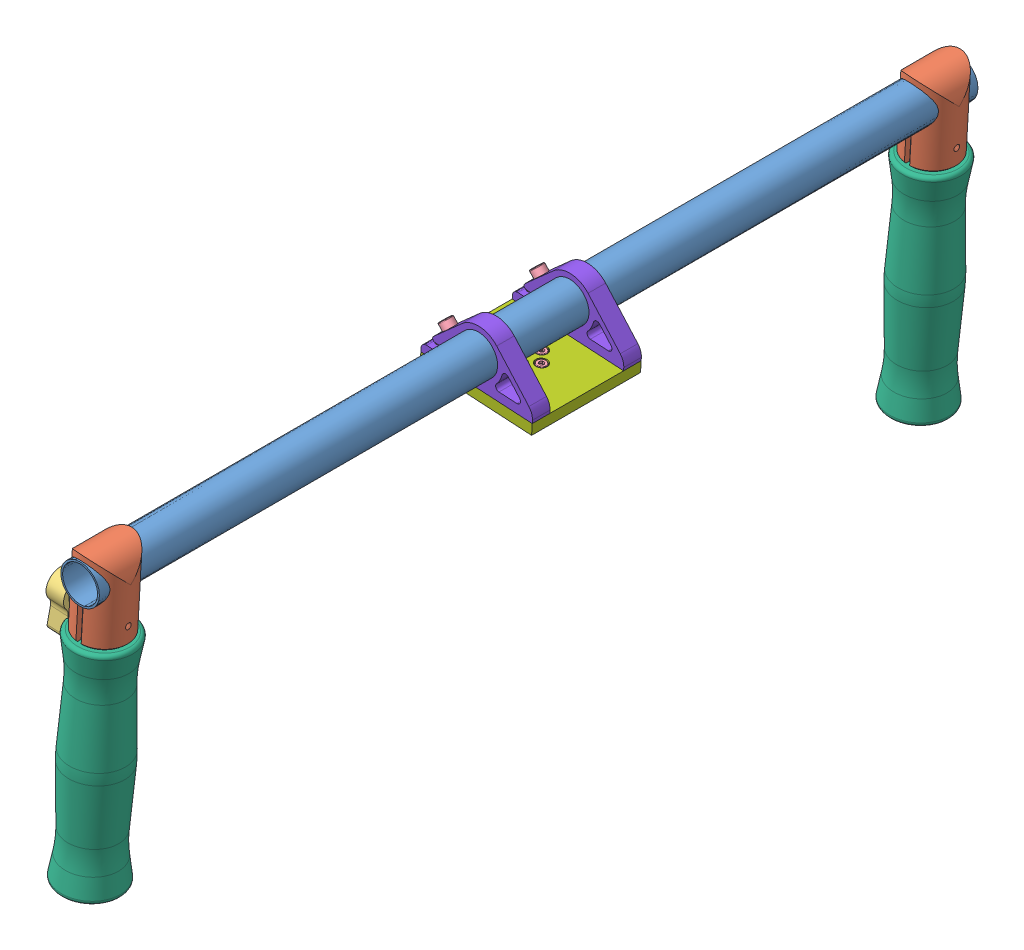
SolidWorks assembly yaw_lowcost_pipe_22mm_holder_4K, configuration По умолчанию. Lengths in mm.
Overall size (66.09 174.99 512.92).
29 component instances, 8 part files, 17 mates.
Components (placement in the parent):
- pipe_22_2_500-1: pipe_22_2_500 [По умолчанию] at (-77.2136 117.9724 -226.0257) x (0.999947 -0.010256 0) z (0 0 1) size (22 22 500)
- handle_holder_22mm-1: handle_holder_22mm [По умолчанию] at (-76.3925 131.9483 259.1774) x (0.998279 -0.058647 0) z (-0.058647 -0.998279 0) size (28 28 45)
- handle_holder_22mm-2: handle_holder_22mm [По умолчанию] at (-76.3925 131.9483 -212.3244) x (0.998279 -0.058647 0) z (-0.058647 -0.998279 0) size (28 28 45)
- flag_screw-4: flag_screw [По умолчанию] at (-77.412 147.1518 -231.8909) x (0.05844 0.994748 0.084026) z (-0.004928 -0.083881 0.996464) size (16 29 29)
  - flag-1: flag [По умолчанию] at (-48.2962 13.0906 23.7085) size (16 10 29)
  - socket head cap screw_din_1-1: socket head cap screw_din_1 [DIN 912 M4 x 25 --- 25N] at (-48.2962 23.0906 23.7085) x (0 -1 0) z (-0.387543 0 0.921852) size (29 7 7)
  - plain washer 6902 type abc_din-1: plain washer 6902 type abc_din [DIN 6902-A4.55] at (-48.2962 13.0906 23.7085) x (0 -1 0) z (-0.000413 0 1) size (1 10 10)
- flag_screw-5: flag_screw [По умолчанию] at (-78.5556 127.6853 303.4175) x (0.008709 0.14824 0.988913) z (-0.057997 -0.987211 0.148496) size (16 29 29)
  - flag-1: flag [По умолчанию] at (-48.2962 13.0906 23.7085) size (16 10 29)
  - socket head cap screw_din_1-1: socket head cap screw_din_1 [DIN 912 M4 x 25 --- 25N] at (-48.2962 23.0906 23.7085) x (0 -1 0) z (-0.387543 0 0.921852) size (29 7 7)
  - plain washer 6902 type abc_din-1: plain washer 6902 type abc_din [DIN 6902-A4.55] at (-48.2962 13.0906 23.7085) x (0 -1 0) z (-0.000413 0 1) size (1 10 10)
- pipe_22_2_500-2: pipe_22_2_500 [150mm] at (-77.976 104.9948 -212.3244) x (-0.658186 0.038667 0.751862) z (-0.058647 -0.998279 0) size (22 22 145)
- pipe_22_2_500-3: pipe_22_2_500 [150mm] at (-77.976 104.9948 259.1774) x (0.99525 -0.058469 0.077844) z (-0.058647 -0.998279 0) size (22 22 145)
- neopren-1: neopren [По умолчанию] at (-79.0316 87.0258 259.1774) x (0.6577 -0.038639 0.752289) z (-0.750994 0.04412 0.658834) size (34.36 127 34.36)
- neopren-2: neopren [По умолчанию] at (-79.0316 87.0258 -212.3244) x (0.998279 -0.058647 0) z (0 0 1) size (34.36 127 34.36)
- lowcost_handle_holder-1: lowcost_handle_holder [По умолчанию] at (-103.6025 70.0667 71.265) x (0 0 1) z (0.058647 0.998279 0) size (62 63.5 46)
  - yaw_lowcost_pipe_22mm_holder_plate-1: yaw_lowcost_pipe_22mm_holder_plate [По умолчанию] at (-54.9011 23.534 26.371) size (62 63.5 6)
  - pipe_22_holder_3-1: pipe_22_holder_3 [По умолчанию] at (-75.9011 23.534 49.371) x (0 -1 0) z (-1 0 0) size (63.5 31 10)
  - pipe_22_holder_3-2: pipe_22_holder_3 [По умолчанию] at (-23.9011 23.534 49.371) x (0 -1 0) z (-1 0 0) size (63.5 31 10)
  - socket head cap screw_din_1-1: socket head cap screw_din_1 [DIN 912 M4 x 6 --- 6N] at (-28.9011 -3.216 26.371) x (0 0 1) z (-1 0 0) size (10 7 7)
  - socket head cap screw_din_1-2: socket head cap screw_din_1 [DIN 912 M4 x 6 --- 6N] at (-28.9011 50.284 26.371) x (0 0 1) z (-1 0 0) size (10 7 7)
  - socket head cap screw_din_1-3: socket head cap screw_din_1 [DIN 912 M4 x 6 --- 6N] at (-80.9011 50.284 26.371) x (0 0 1) z (-1 0 0) size (10 7 7)
  - socket head cap screw_din_1-4: socket head cap screw_din_1 [DIN 912 M4 x 6 --- 6N] at (-80.9011 -3.216 26.371) x (0 0 1) z (-1 0 0) size (10 7 7)
  - socket head cap screw_din_1-5: socket head cap screw_din_1 [DIN 912 M3 x 12 --- 12N] at (-54.9011 29.534 32.371) x (0 0 -1) z (1 0 0) size (15 5.5 5.5)
  - socket head cap screw_din_1-6: socket head cap screw_din_1 [DIN 912 M3 x 12 --- 12N] at (-48.9011 23.534 32.371) x (0 0 -1) z (1 0 0) size (15 5.5 5.5)
  - socket head cap screw_din_1-7: socket head cap screw_din_1 [DIN 912 M3 x 12 --- 12N] at (-60.9011 23.534 32.371) x (0 0 -1) z (1 0 0) size (15 5.5 5.5)
  - socket head cap screw_din_1-8: socket head cap screw_din_1 [DIN 912 M3 x 12 --- 12N] at (-54.9011 17.534 32.371) x (0 0 -1) z (1 0 0) size (15 5.5 5.5)
  - socket head cap screw_din_1-11: socket head cap screw_din_1 [DIN 912 M4 x 16 --- 16N] at (-80.9011 -0.2649 51.0031) x (0 0.707898 -0.706314) z (0.706314 0.499999 0.50112) size (20 7 7)
  - socket head cap screw_din_1-12: socket head cap screw_din_1 [DIN 912 M4 x 16 --- 16N] at (-28.9011 -0.2649 51.0031) x (0 0.707898 -0.706314) z (0.706314 0.499999 0.50112) size (20 7 7)
Mates (geometry in assembly coordinates):
- Концентричный27: concentric anti-aligned: cylinder of pipe_22_2_500-1 through (-77.2136 117.9724 273.9743) axis (0 0 -1) radius 11; cylinder of handle_holder_22mm-1 through (-77.2136 117.9724 245.1774) axis (0 0 1) radius 10.925
- Концентричный28: concentric anti-aligned: cylinder of pipe_22_2_500-1 through (-77.2136 117.9724 273.9743) axis (0 0 -1) radius 11; cylinder of handle_holder_22mm-2 through (-77.2136 117.9724 -226.3244) axis (0 0 1) radius 10.925
- Концентричный30: concentric aligned: cylinder of handle_holder_22mm-2 through (-92.4211 97.8297 -212.3244) axis (-0.998279 0.058647 0) radius 2.25; cylinder of flag_screw-4/socket head cap screw_din_1-1 through (-135.0975 100.3368 -212.3244) axis (-0.998279 0.058647 0) radius 2
- Касательность3: tangent anti-aligned: cylinder of handle_holder_22mm-2 through (-79.0316 87.0258 -212.3244) axis (0.058647 0.998279 0) radius 14; plane of flag_screw-4/plain washer 6902 type abc_din-1 through (-92.4211 97.8297 -212.3244) normal (0.998279 -0.058647 0)
- Концентричный31: concentric aligned: cylinder of handle_holder_22mm-1 through (-92.4211 97.8297 259.1774) axis (-0.998279 0.058647 0) radius 2.25; cylinder of flag_screw-5/socket head cap screw_din_1-1 through (-135.0975 100.3368 259.1774) axis (-0.998279 0.058647 0) radius 2
- Касательность4: tangent anti-aligned: cylinder of handle_holder_22mm-1 through (-79.0316 87.0258 259.1774) axis (0.058647 0.998279 0) radius 14; plane of flag_screw-5/plain washer 6902 type abc_din-1 through (-92.4211 97.8297 259.1774) normal (0.998279 -0.058647 0)
- Концентричный33: concentric anti-aligned: cylinder of handle_holder_22mm-2 through (-77.2136 117.9724 -212.3244) axis (-0.058647 -0.998279 0) radius 11; cylinder of pipe_22_2_500-2 through (-86.4799 -39.7556 -212.3244) axis (0.058647 0.998279 0) radius 11
- Расстояние2: distance = 127 mm aligned: plane of pipe_22_2_500-2 through (-86.4799 -39.7556 -212.3244) normal (-0.058647 -0.998279 0); plane of handle_holder_22mm-2 through (-79.0316 87.0258 -212.3244) normal (-0.058647 -0.998279 0)
- Концентричный34: concentric anti-aligned: cylinder of handle_holder_22mm-1 through (-77.2136 117.9724 259.1774) axis (-0.058647 -0.998279 0) radius 11; cylinder of pipe_22_2_500-3 through (-86.4799 -39.7556 259.1774) axis (0.058647 0.998279 0) radius 11
- Расстояние3: distance = 127 mm aligned: plane of pipe_22_2_500-3 through (-86.4799 -39.7556 259.1774) normal (-0.058647 -0.998279 0); plane of handle_holder_22mm-1 through (-79.0316 87.0258 259.1774) normal (-0.058647 -0.998279 0)
- Концентричный35: concentric aligned: cylinder of pipe_22_2_500-2 through (-86.4799 -39.7556 -212.3244) axis (0.058647 0.998279 0) radius 11; cylinder of neopren-2 through (-86.4799 -39.7556 -212.3244) axis (0.058647 0.998279 0) radius 11
- Совпадение48: coincident aligned: plane of pipe_22_2_500-2 through (-86.4799 -39.7556 -212.3244) normal (-0.058647 -0.998279 0); plane of neopren-2 through (-86.4799 -39.7556 -212.3244) normal (-0.058647 -0.998279 0)
- Концентричный36: concentric aligned: cylinder of pipe_22_2_500-3 through (-86.4799 -39.7556 259.1774) axis (0.058647 0.998279 0) radius 11; cylinder of neopren-1 through (-86.4799 -39.7556 259.1774) axis (0.058647 0.998279 0) radius 11
- Совпадение49: coincident aligned: plane of pipe_22_2_500-3 through (-86.4799 -39.7556 259.1774) normal (-0.058647 -0.998279 0); plane of neopren-1 through (-86.4799 -39.7556 259.1774) normal (-0.058647 -0.998279 0)
- Концентричный37: concentric anti-aligned: cylinder of pipe_22_2_500-1 through (-77.2136 117.9724 273.9743) axis (0 0 -1) radius 11; cylinder of lowcost_handle_holder-1/pipe_22_holder_3-2 through (-77.2136 117.9724 37.3639) axis (0 0 1) radius 11
- Параллельность1: parallel aligned: plane of neopren-1 through (-86.4799 -39.7556 259.1774) normal (-0.058647 -0.998279 0); plane of lowcost_handle_holder-1/yaw_lowcost_pipe_22mm_holder_plate-1 through (-78.5625 95.012 16.3639) normal (-0.058647 -0.998279 0)
- Параллельность2: parallel aligned: plane of neopren-1 through (-86.4799 -39.7556 259.1774) normal (-0.058647 -0.998279 0); plane of neopren-2 through (-86.4799 -39.7556 -212.3244) normal (-0.058647 -0.998279 0)
